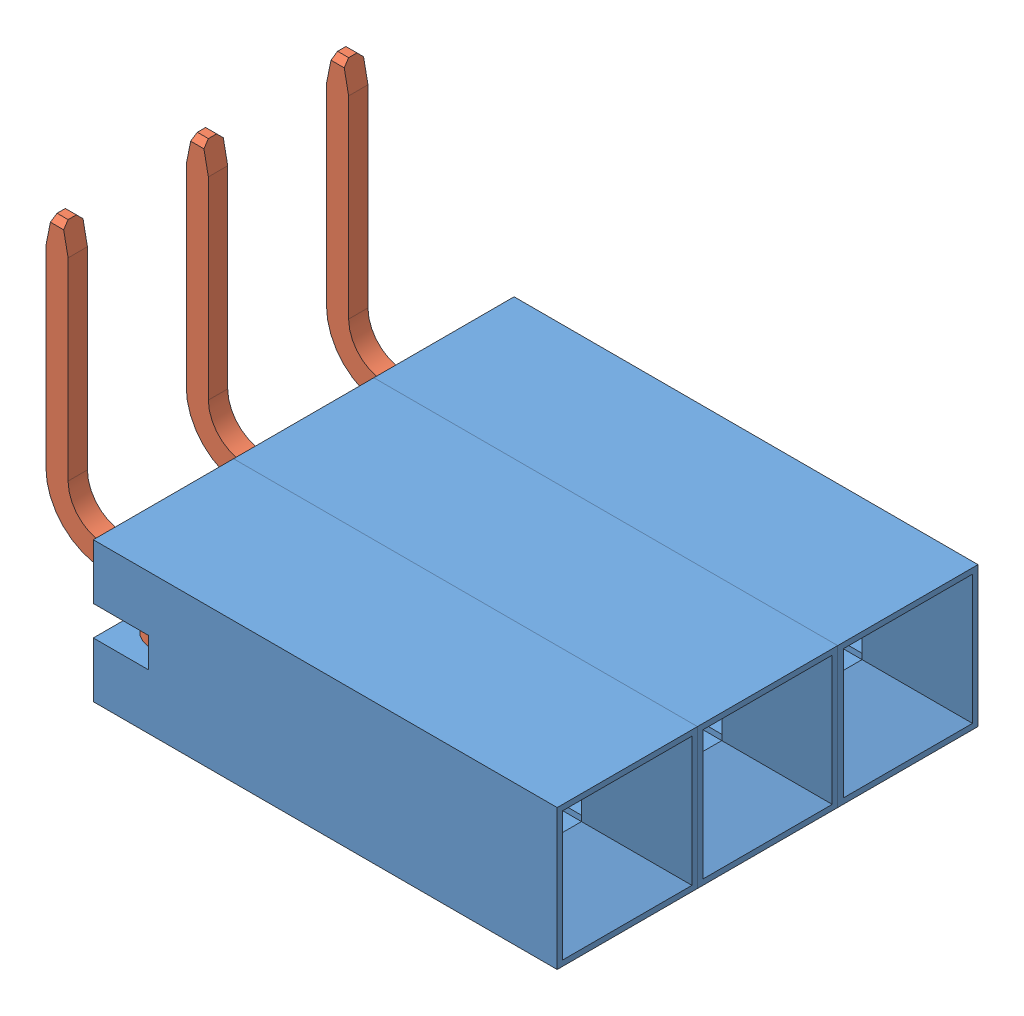
SolidWorks assembly H254_90deg_3pin, configuration Default. Lengths in mm.
Overall size (10.36 6.14 7.62).
9 component instances, 2 part files, 4 mates.
Components (placement in the parent):
- FrameAndPin_H254_90deg-1: FrameAndPin_H254_90deg [Default] at origin size (10.36 6.14 2.54)
  - frame_H254-1: frame_H254 [Default] at origin size (8.4 2.54 2.54)
  - pin-90deg-1: pin-90deg [Default] at (-0.0461 1.2682 1.27) x (0 0 -1) z (0.999998 -0.002105 0) size (1.95 5.07 7.58)
- FrameAndPin_H254_90deg-2: FrameAndPin_H254_90deg [Default] at (0 0 -2.54) size (10.36 6.14 2.54)
  - frame_H254-1: frame_H254 [Default] at origin size (8.4 2.54 2.54)
  - pin-90deg-1: pin-90deg [Default] at (-0.0461 1.2682 1.27) x (0 0 -1) z (0.999998 -0.002105 0) size (1.95 5.07 7.58)
- FrameAndPin_H254_90deg-4: FrameAndPin_H254_90deg [Default] at (0 0 -5.08) size (10.36 6.14 2.54)
  - frame_H254-1: frame_H254 [Default] at origin size (8.4 2.54 2.54)
  - pin-90deg-1: pin-90deg [Default] at (-0.0461 1.2682 1.27) x (0 0 -1) z (0.999998 -0.002105 0) size (1.95 5.07 7.58)
Mates (geometry in assembly coordinates):
- Coincident1: coincident aligned: line of FrameAndPin_H254_90deg-1/frame_H254-1 through (8.4 8.4 2.54) axis (0 -1 0); line of FrameAndPin_H254_90deg-2/frame_H254-1 through (8.4 8.4 2.54) axis (0 -1 0)
- Coincident2: coincident aligned: line of FrameAndPin_H254_90deg-1/frame_H254-1 through (2.54 8.4 0) axis (0 0 1); line of FrameAndPin_H254_90deg-2/frame_H254-1 through (2.54 8.4 0) axis (0 0 1)
- Coincident3: coincident aligned: line of FrameAndPin_H254_90deg-2/frame_H254-1 through (8.4 2.54 -2.54) axis (-1 0 0); line of FrameAndPin_H254_90deg-4/frame_H254-1 through (8.4 2.54 -2.54) axis (-1 0 0)
- Coincident4: coincident aligned: line of FrameAndPin_H254_90deg-2/frame_H254-1 through (8.4 0 -2.54) axis (0 1 0); line of FrameAndPin_H254_90deg-4/frame_H254-1 through (8.4 0 -2.54) axis (0 1 0)
